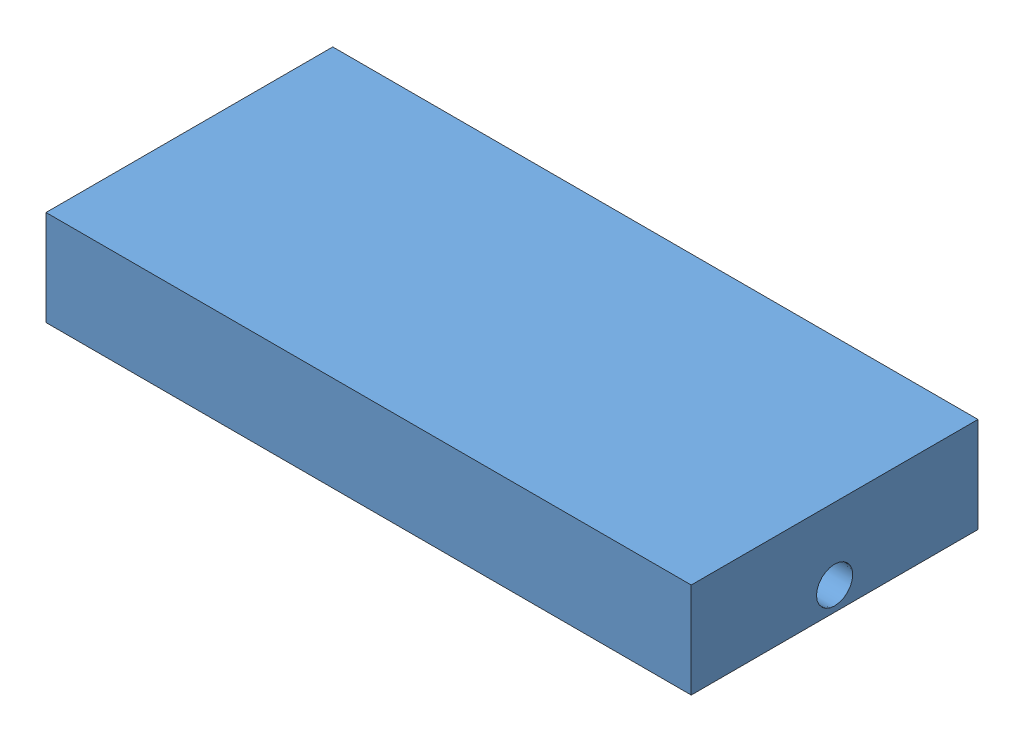
SolidWorks assembly Assem3, configuration Default. Lengths in mm.
Overall size (228.6 34.73 101.6).
2 component instances, 2 part files, 2 mates.
Components (placement in the parent):
- box-1: box [Default] at origin size (228.6 33.78 101.6)
- Assem2 part-1: Assem2 part [Default] at (-123.465 155.8535 -44.3815) x (-1 0 0) z (0 -1 0) size (203.2 76.2 22)
Mates (geometry in assembly coordinates):
- Parallel3: parallel aligned: line of box-1 through (-102.87 -17.78 -39.37) axis (0 0 1); line of Assem2 part-1 through (-101.4571 -19.38 -38.483) axis (0 0 1)
- Coincident8: coincident anti-aligned: plane of box-1 through (102.87 -17.78 29.21) normal (0 -1 0); plane of Assem2 part-1 through (0.1429 -17.78 -0.383) normal (0 1 0)
